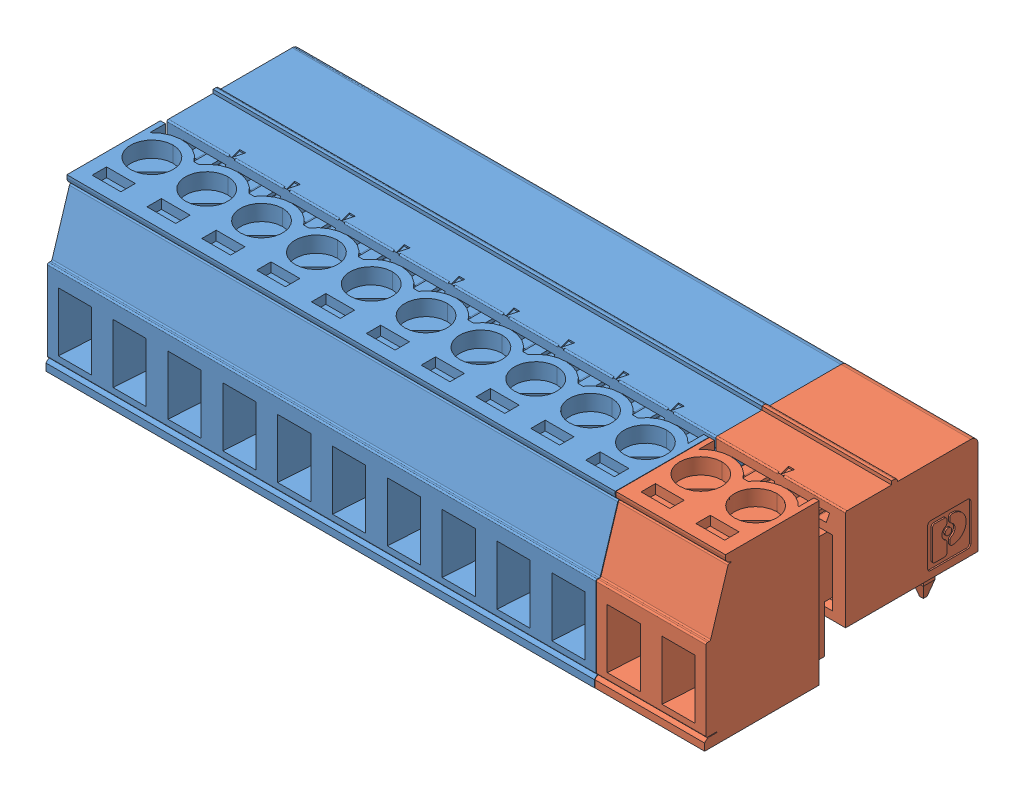
SolidWorks assembly Assem1, configuration Default. Lengths in mm.
Overall size (47.16 11.31 18.42).
2 component instances, 2 part files, 0 mates.
Components (placement in the parent):
- 3_81mm_10pin_RA.step-1: 3_81mm_10pin_RA.step [Default] at (-18.8284 18.0769 33.9044) size (39.49 11.28 18.4)
- 381-2p.step-1: 381-2p.step [Default] at (19.3257 18.105 33.9199) size (9.01 11.28 18.4)
